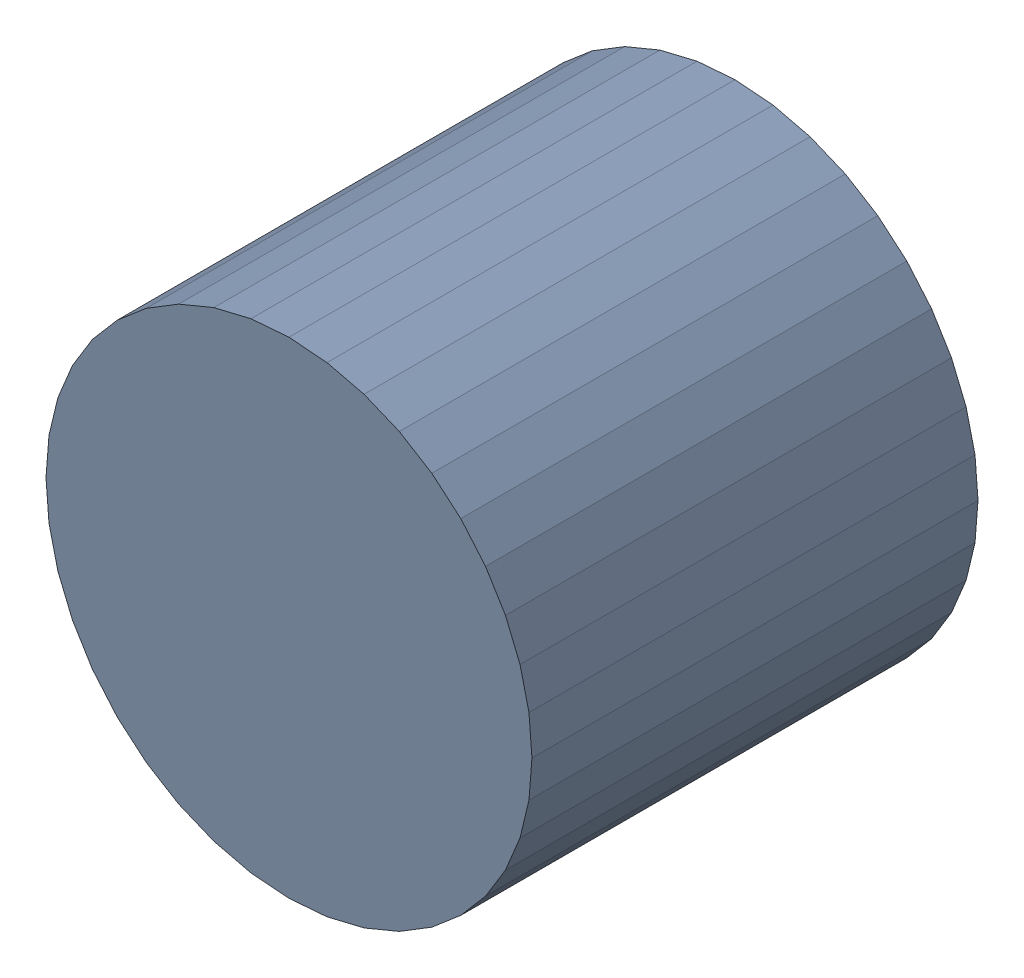
SolidWorks assembly CoutB2_1Kanaloa_v2.0.0_Power, configuration Default. Lengths in mm.
Overall size (6.32 6.32 5.8).
2 component instances, 1 part files, 0 mates.
Components (placement in the parent):
- 352892112-1: 352892112 [Default] at (142.75 45.225 0) size (6.32 6.32 5.8)
  - Extruded_11-1: Extruded_11 [Default] at origin size (6.32 6.32 5.8)
